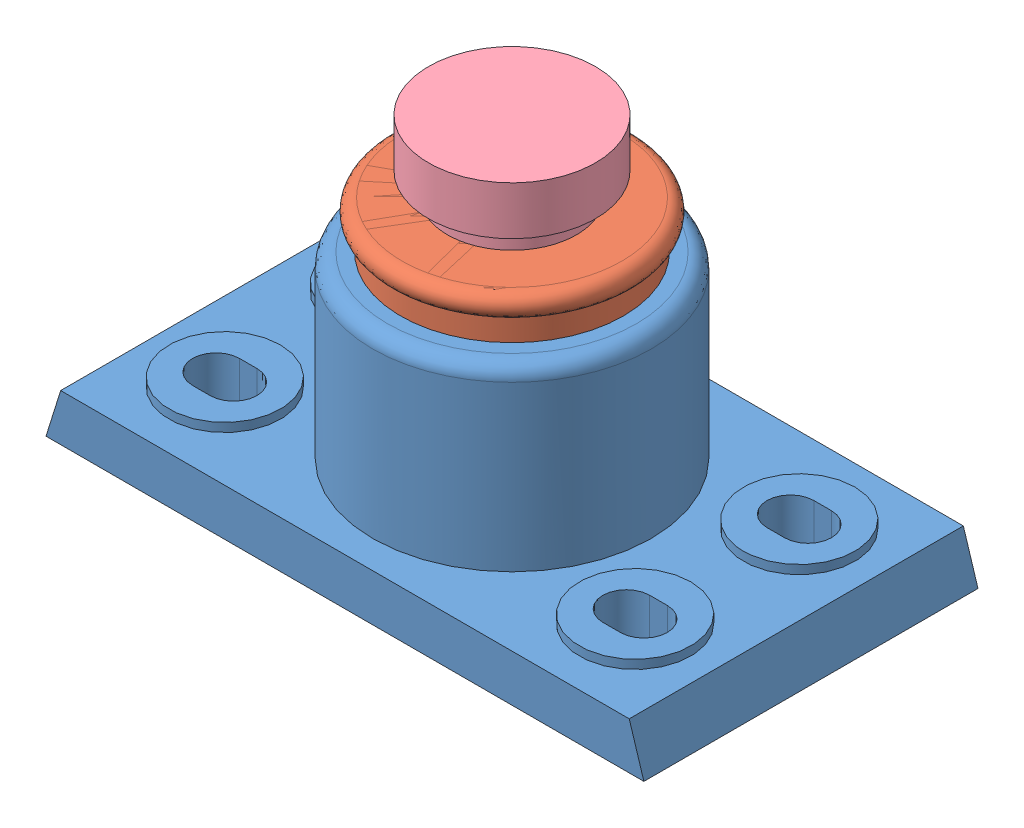
SolidWorks assembly Assem1, configuration Default. Lengths in mm.
Overall size (204 117.51 114).
4 component instances, 4 part files, 6 mates.
Components (placement in the parent):
- casting-2: casting [Default] at (-12.5092 -30.3515 203.6394) size (204 77 114)
- bush-3: bush [Default] at (-12.5092 -30.3515 203.6394) x (0.007439 0 0.999972) z (-0.999972 0 0.007439) size (83 77 83)
- pad-2: pad [Default] at (-12.5092 -30.3515 203.6394) x (0.967811 0 -0.251677) z (0.251677 0 0.967811) size (44 73.25 44)
- shaft-1: shaft [Default] at (-12.5092 -20.3515 203.6394) size (57 91.51 57)
Mates (geometry in assembly coordinates):
- Lock2: lock: unknown of casting-2; unknown of bush-3
- Lock3: lock: unknown of casting-2; unknown of bush-3
- Concentric5: concentric aligned: cylinder of bush-3 through (-12.5092 -30.3515 203.6394) axis (0 -1 0) radius 22; cylinder of pad-2 through (-12.5092 -30.3515 203.6394) axis (0 -1 0) radius 22
- Lock4: lock: unknown of bush-3; unknown of pad-2
- Lock6: lock: unknown of bush-3; unknown of shaft-1
- Lock5: lock: unknown of pad-2; unknown of shaft-1
